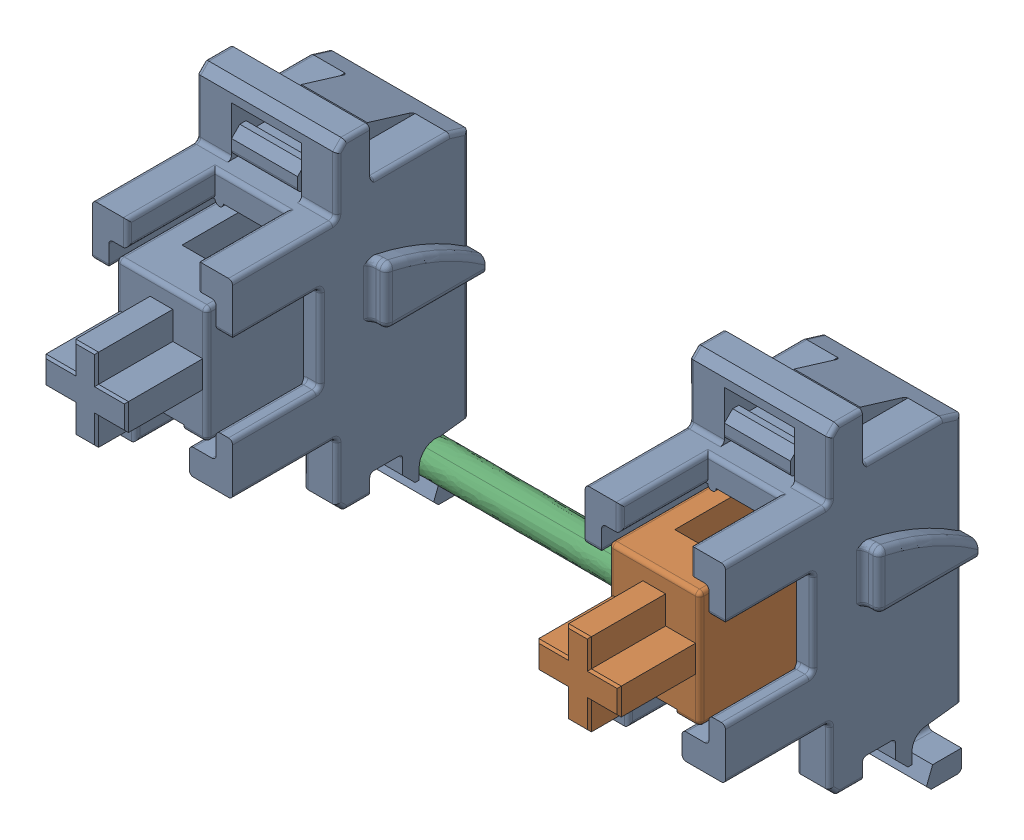
SolidWorks assembly AS_TEST_STABIL_ASM, configuration Default. Lengths in mm.
Overall size (34.56 23.73 38.46).
5 component instances, 3 part files, 0 mates.
Components (placement in the parent):
- STABIL_DOWN_MX-1: STABIL_DOWN_MX [Default] at (4.2 9.8 23.0591) size (8.52 17.6 11.65)
- STABIL_MX-1: STABIL_MX [Default] at (2 12.625 23.7591) x (0 -1 0) z (-1 0 0) size (8.3 11.95 4.4)
- STABIL_DOWN_MX-2: STABIL_DOWN_MX [Default] at (28.1 9.8 23.0591) size (8.52 17.6 11.65)
- STABIL_MX-2: STABIL_MX [Default] at (25.9 12.625 23.7591) x (0 -1 0) z (-1 0 0) size (8.3 11.95 4.4)
- MX_METAL-1: MX_METAL [Default] at (16.15 11.2814 26.5599) x (1 0 0) z (0 0.587785 -0.809017) size (25.52 12.2 1.68)
